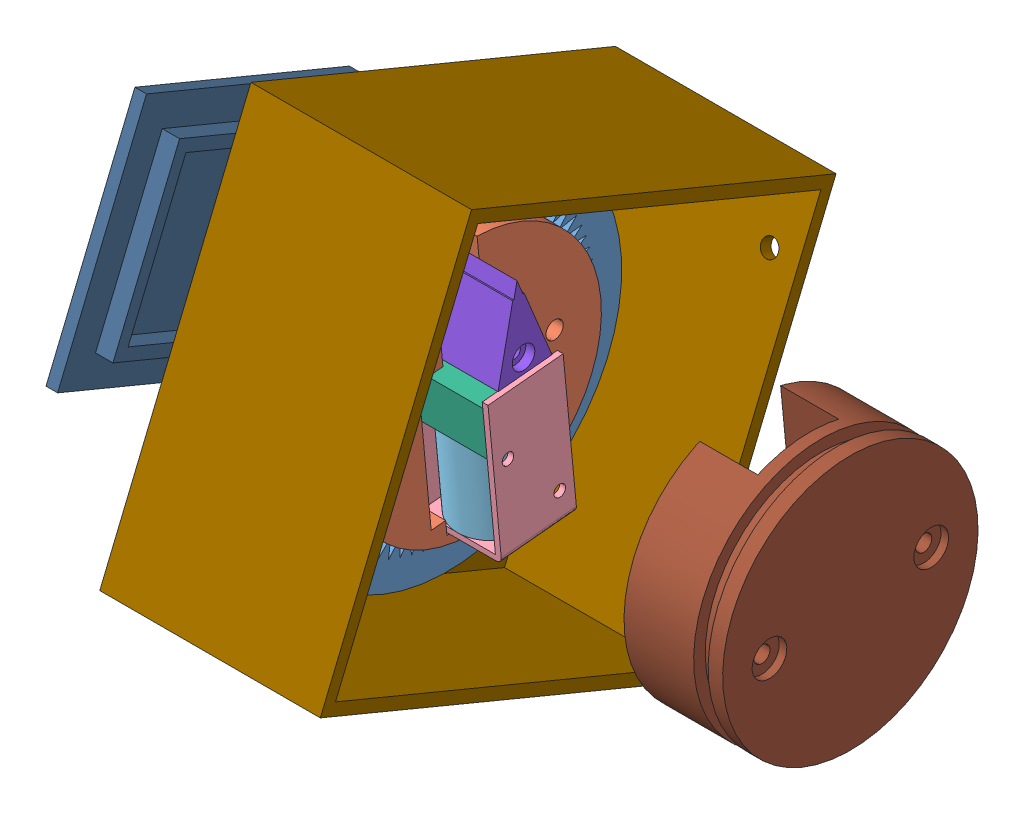
SolidWorks assembly Prototype_V1, configuration Default. Lengths in mm.
Overall size (112.45 88.86 88.86).
14 component instances, 12 part files, 22 mates.
Components (placement in the parent):
- Locking_plate_string_connector-1: Locking_plate_string_connector [Default] at (-26.6415 38.7296 61.615) size (11.5 60 60)
- Shaft_solenoid_support-1: Shaft_solenoid_support [Default] at (-14.6415 38.7296 61.615) x (-1 0 0) z (0 -0.094974 0.99548) size (22.5 44 44)
- deep groove ball bearings gb-1: deep groove ball bearings gb [Rolling bearings 637-8 GB 276-94] at (-26.3915 38.7296 61.615) x (-1 0 0) z (0 -0.059575 -0.998224) size (3.5 12 12)
- Coil Spring-1: Coil Spring [Default] at (-152.5058 12.4636 44.486) x (0.996832 -0.079534 -0.000129) z (-0.079524 -0.996731 0.014223) size (22.08 22.02 3.31) (hidden)
- Solenoid-1: Solenoid [Default] at (-10.0202 52.0749 83.3379) x (1 0 0) z (0 0.094974 -0.99548) size (15 40.57 13)
  - External part-1: External part [Default] at (4.8787 9.4049 13.8573) x (0 -1 0) z (0 0 1) size (25 15 13)
  - Coil-2: Coil [Default] at (-2.6213 18.4049 20.3573) size (13 15 13)
  - Front-1: Front [Default] at (3.8787 18.4049 13.8573) x (0 0 1) z (0 -1 0) size (13 13 8)
  - Plunger Solenoid-1: Plunger Solenoid [Default] at (-2.6213 28.4049 20.3573) x (0 -1 0) z (0 0 1) size (25 6 6)
  - Solenoid Insert Verowhite-1: Solenoid Insert Verowhite [Default] at (-7.6213 12.9703 20.3372) x (0 0 -1) z (0 -1 0) size (9.32 15 14.57)
- Package_only_mechanical_withtou_plunger-1: Package_only_mechanical_withtou_plunger [Default] at (3.3585 -5.6994 43.2287) x (0 0.923756 -0.382983) z (0 0.382983 0.923756) size (68 38 68)
- deep groove ball bearings gb-2: deep groove ball bearings gb [Rolling bearings 637-8 GB 276-94] at (-27.8915 38.7296 61.615) x (-1 0 0) z (0 -0.059575 -0.998224) size (3.5 12 12)
- Cover-1: Cover [Default] at (-62.1988 36.2327 68.2711) x (0 0.382983 0.923756) z (1 0 0) size (40 40 5)
- String_connector-1: String_connector [Default] at (50.2509 38.7296 61.615) x (0 -0.99548 -0.094974) z (-1 0 0) size (44 44 17)
Mates (geometry in assembly coordinates):
- Concentric2: concentric anti-aligned: cylinder of Locking_plate_string_connector-1 through (-19.1415 38.7296 61.615) axis (-1 0 0) radius 30; cylinder of Shaft_solenoid_support-1 through (-24.6415 38.7296 61.615) axis (1 0 0) radius 22
- Concentric3: concentric anti-aligned: cylinder of Locking_plate_string_connector-1 through (-19.1415 38.7296 61.615) axis (-1 0 0) radius 30; cylinder of deep groove ball bearings gb-1 through (-17.6808 38.7296 61.615) axis (1 0 0) radius 6
- Coincident4: coincident anti-aligned: plane of Shaft_solenoid_support-1 through (-20.1415 19.8785 53.287) normal (0 -0.094974 0.99548); plane of Solenoid-1/External part-1 through (-5.1415 45.2633 55.7088) normal (0 0.094974 -0.99548)
- LimitDistance1: limit distance = 0 mm anti-aligned: plane of Shaft_solenoid_support-1 through (-20.1415 38.7296 61.615) normal (1 0 0); plane of Solenoid-1/External part-1 through (-20.1415 45.2633 55.7088) normal (-1 0 0)
- Coincident5: coincident anti-aligned: plane of Shaft_solenoid_support-1 through (-14.6415 44.6459 62.1794) normal (0 -0.99548 -0.094974); plane of Solenoid-1/External part-1 through (-5.1415 45.2633 55.7088) normal (0 0.99548 0.094974)
- Concentric4: concentric anti-aligned: cylinder of Shaft_solenoid_support-1 through (-24.6415 38.7296 61.615) axis (1 0 0) radius 22; cylinder of Package_only_mechanical_withtou_plunger-1 through (-29.6415 38.7296 61.615) axis (-1 0 0) radius 10.5
- Coincident6: coincident aligned: plane of Package_only_mechanical_withtou_plunger-1 through (-29.6415 38.7296 61.615) normal (-1 0 0); plane of deep groove ball bearings gb-2 through (-29.6415 44.719 61.2575) normal (-1 0 0)
- Concentric5: concentric anti-aligned: cylinder of Package_only_mechanical_withtou_plunger-1 through (3.3585 38.7296 61.615) axis (-1 0 0) radius 6.05; cylinder of deep groove ball bearings gb-2 through (-19.1808 38.7296 61.615) axis (1 0 0) radius 6
- Coincident10: coincident aligned: plane of Locking_plate_string_connector-1 through (-24.6415 38.7296 61.615) normal (1 0 0); plane of deep groove ball bearings gb-1 through (-24.6415 44.719 61.2575) normal (1 0 0)
- Coincident11: coincident anti-aligned: plane of Locking_plate_string_connector-1 through (-24.6415 38.7296 61.615) normal (1 0 0); plane of Shaft_solenoid_support-1 through (-24.6415 38.7296 61.615) normal (-1 0 0)
- Parallel1: parallel anti-aligned: plane of Package_only_mechanical_withtou_plunger-1 through (-31.6415 19.1286 53.5034) normal (0 0.382983 0.923756); plane of Cover-1 through (-57.1988 46.8412 42.0139) normal (0 -0.382983 -0.923756)
- Parallel2: parallel aligned: plane of Package_only_mechanical_withtou_plunger-1 through (-34.6415 -5.6994 43.2287) normal (-1 0 0); plane of Cover-1 through (-62.1988 36.2327 68.2711) normal (-1 0 0)
- Parallel3: parallel anti-aligned: plane of Package_only_mechanical_withtou_plunger-1 through (-31.6415 19.1286 53.5034) normal (0 0.382983 0.923756); plane of Cover-1 through (-57.1988 46.8412 42.0139) normal (0 -0.382983 -0.923756)
- Concentric6: concentric aligned: cylinder of Shaft_solenoid_support-1 through (-37.1415 38.7296 61.615) axis (1 0 0) radius 4; cylinder of deep groove ball bearings gb-2 through (-20.9201 38.7296 61.615) axis (1 0 0) radius 4
- Concentric7: concentric anti-aligned: cylinder of Shaft_solenoid_support-1 through (-37.1415 38.7296 61.615) axis (1 0 0) radius 4; cylinder of Package_only_mechanical_withtou_plunger-1 through (-29.6415 38.7296 61.615) axis (-1 0 0) radius 10.5
- LimitDistance2: limit distance = 0 mm anti-aligned: plane of Package_only_mechanical_withtou_plunger-1 through (-26.6415 -5.6994 43.2287) normal (1 0 0); plane of Locking_plate_string_connector-1 through (-26.6415 38.7296 61.615) normal (-1 0 0)
- Concentric9: concentric aligned: cylinder of Shaft_solenoid_support-1 through (-24.6415 38.7296 61.615) axis (1 0 0) radius 22; cylinder of String_connector-1 through (33.2509 38.7296 61.615) axis (1 0 0) radius 22
- LimitDistance3: limit distance = 47.8924 mm anti-aligned: plane of Shaft_solenoid_support-1 through (-14.6415 38.7296 61.615) normal (1 0 0); plane of String_connector-1 through (33.2509 38.7296 61.615) normal (-1 0 0)
- Concentric10: concentric aligned: cylinder of Shaft_solenoid_support-1 through (-21.6415 37.4 75.5517) axis (1 0 0) radius 1.5; cylinder of String_connector-1 through (33.2509 37.4 75.5517) axis (1 0 0) radius 1.4
- Coincident12: coincident anti-aligned: plane of Package_only_mechanical_withtou_plunger-1 through (-31.6415 19.1286 53.5034) normal (0 0.923756 -0.382983); plane of Cover-1 through (-57.1988 30.6181 81.216) normal (0 -0.923756 0.382983)
- Coincident13: coincident anti-aligned: plane of Package_only_mechanical_withtou_plunger-1 through (-31.6415 19.1286 53.5034) normal (0 0.382983 0.923756); plane of Cover-1 through (-57.1988 46.8412 42.0139) normal (0 -0.382983 -0.923756)
- Coincident14: coincident anti-aligned: plane of Locking_plate_string_connector-1 through (-26.6415 38.7296 61.615) normal (-1 0 0); plane of Package_only_mechanical_withtou_plunger-1 through (-26.6415 -5.6994 43.2287) normal (1 0 0)
